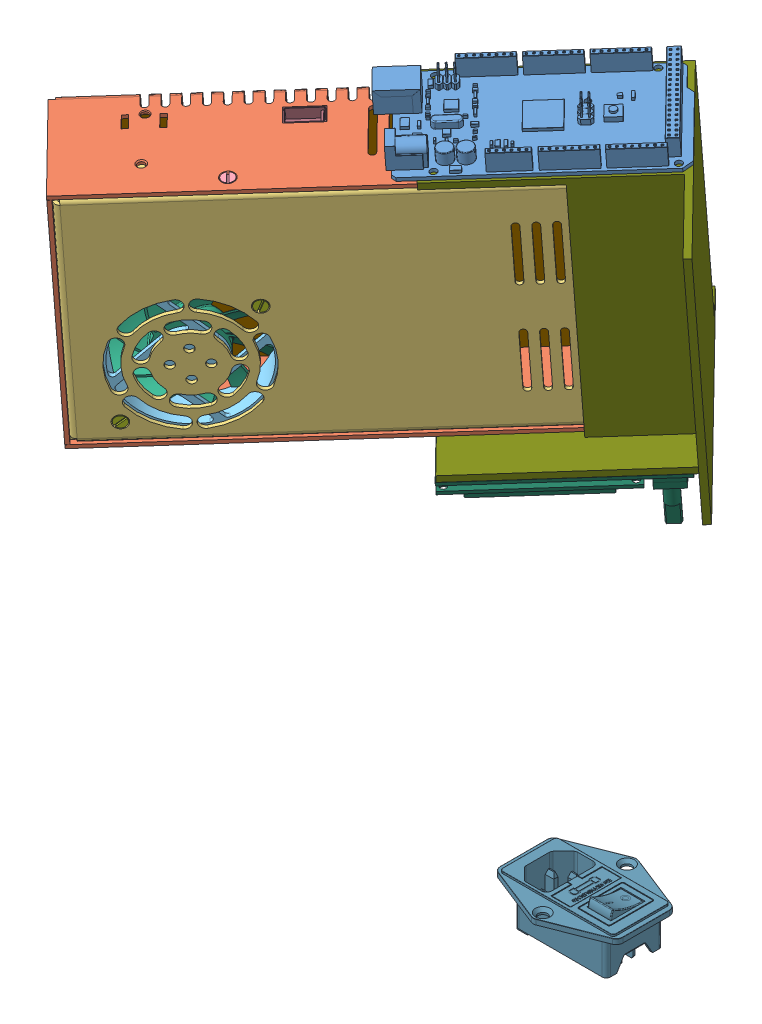
SolidWorks assembly _commandCenter, configuration Default. Lengths in mm.
Overall size (275.01 269.14 216.02).
51 component instances, 16 part files, 8 mates.
Components (placement in the parent):
- ArduinoMega-1: ArduinoMega [Default] at (-17.2246 278.8419 82.4218) x (-0.718489 -0.053184 0.693502) z (-0.041616 -0.991999 -0.119192) size (107.95 53.42 12.95)
- POWER 12V 30A.stp-1: POWER 12V 30A.stp [Default] at (-1.3313 279.7811 30.0341) x (0.718489 0.053184 -0.693502) z (-0.041616 -0.991999 -0.119192) size (215 51.26 117.39)
  - SWP (Basis).stp-1: SWP (Basis).stp [Default] at (0 1.75 57) x (1 0 0) z (0 1 0) size (215 114.01 51.26)
  - SWP (Deksel).stp-1: SWP (Deksel).stp [Default] at (-18.25 51.25 57) x (1 0 0) z (0 1 0) size (195 110.5 25.75)
  - Slotted Countersunk Flat Head Screw_DIN_ISO 2009 - M3 x 5 --- 5N.stp-1: Slotted Countersunk Flat Head Screw_DIN_ISO 2009 - M3 x 5 --- 5N.stp [Default] at (-154 44.75 114) x (0 0 -1) z (-0.992092 0.125515 0) size (5 5.5 5.44)
  - Slotted Countersunk Flat Head Screw_DIN_ISO 2009 - M3 x 5 --- 5N.stp-2: Slotted Countersunk Flat Head Screw_DIN_ISO 2009 - M3 x 5 --- 5N.stp [Default] at (-33 44.75 114) x (0 0 -1) z (0.278156 0.960536 0) size (5 5.5 5.44)
  - Slotted Countersunk Flat Head Screw_DIN_ISO 2009 - M3 x 5 --- 5N.stp-3: Slotted Countersunk Flat Head Screw_DIN_ISO 2009 - M3 x 5 --- 5N.stp [Default] at (-154 44.75 0) x (0 0 1) z (0 1 0) size (5 5.5 5.44)
  - Slotted Countersunk Flat Head Screw_DIN_ISO 2009 - M3 x 5 --- 5N.stp-4: Slotted Countersunk Flat Head Screw_DIN_ISO 2009 - M3 x 5 --- 5N.stp [Default] at (-33 44.75 0) x (0 0 1) z (-0.877705 -0.479201 0) size (5 5.5 5.44)
  - Slotted Countersunk Flat Head Screw_DIN_ISO 2009 - M3 x 5 --- 5N.stp-5: Slotted Countersunk Flat Head Screw_DIN_ISO 2009 - M3 x 5 --- 5N.stp [Default] at (-215 44.75 102) x (1 0 0) z (0 0.869235 -0.494399) size (5 5.5 5.44)
  - Slotted Countersunk Flat Head Screw_DIN_ISO 2009 - M3 x 5 --- 5N.stp-6: Slotted Countersunk Flat Head Screw_DIN_ISO 2009 - M3 x 5 --- 5N.stp [Default] at (-215 44.75 12) x (1 0 0) z (0 0.76206 0.647506) size (5 5.5 5.44)
  - Body 60mm fan.stp-1: Body 60mm fan.stp [Default] at (-170.75 34.3 77.75) x (1 0 0) z (0 1 0) size (59.5 59.5 15.2)
  - Propellor 60mm fan.stp-1: Propellor 60mm fan.stp [Default] at (-170.75 44.3 77.75) x (0.544808 0 -0.838561) z (0 1 0) size (57.61 57.23 10.4)
  - Slotted Countersunk Flat Head Screw_DIN_ISO 2009 - M3 x 20 --- 20N.stp-1: Slotted Countersunk Flat Head Screw_DIN_ISO 2009 - M3 x 20 --- 20N.stp [Default] at (-145.75 51.25 52.75) x (0 -1 0) z (0.364765 0 -0.9311) size (20 5.5 5.44)
  - Slotted Countersunk Flat Head Screw_DIN_ISO 2009 - M3 x 20 --- 20N.stp-2: Slotted Countersunk Flat Head Screw_DIN_ISO 2009 - M3 x 20 --- 20N.stp [Default] at (-195.75 51.25 102.75) x (0 -1 0) z (0.762204 0 -0.647337) size (20 5.5 5.44)
  - SWP (M3 moer).stp-1: SWP (M3 moer).stp [Default] at (-205 0 104.5) x (1 0 0) z (0 1 0) size (8.08 7 3.75)
  - SWP (M3 moer).stp-2: SWP (M3 moer).stp [Default] at (-205 0 9.5) x (1 0 0) z (0 1 0) size (8.08 7 3.75)
  - SWP (M3 moer).stp-3: SWP (M3 moer).stp [Default] at (-117.5 0 50.05) x (1 0 0) z (0 1 0) size (8.08 7 3.75)
  - SWP (M3 moer).stp-4: SWP (M3 moer).stp [Default] at (-27.5 0 104.5) x (1 0 0) z (0 1 0) size (8.08 7 3.75)
  - SWP (M3 moer).stp-5: SWP (M3 moer).stp [Default] at (-27.5 0 9.5) x (1 0 0) z (0 1 0) size (8.08 7 3.75)
  - SWP (PCB).stp-1: SWP (PCB).stp [Default] at (-1.75 9.75 57) x (1 0 0) z (0 1 0) size (211.5 110.5 15.9)
  - SWP (Montage draad).stp-1: SWP (Montage draad).stp [Default] at (-9.8 18.4 88.95) x (0 0 1) z (0 1 0) size (7 9.9 4.25)
  - SWP (Montage draad 2).stp-1: SWP (Montage draad 2).stp [Default] at (-9.8 18.4 88.95) x (1 0 0) z (0 1 0) size (7 7 1)
  - Slotted Cheese Head Screw_DIN_ISO 1207 - M4 x 5 --- 5N.stp-1: Slotted Cheese Head Screw_DIN_ISO 1207 - M4 x 5 --- 5N.stp [Default] at (-9.8 22 88.95) x (0 -1 0) z (0.939291 0 0.343123) size (7.6 7 7)
  - SWP (Montage draad).stp-2: SWP (Montage draad).stp [Default] at (-9.8 18.4 79.45) x (0 0 1) z (0 1 0) size (7 9.9 4.25)
  - SWP (Montage draad).stp-3: SWP (Montage draad).stp [Default] at (-9.8 18.4 69.95) x (0 0 1) z (0 1 0) size (7 9.9 4.25)
  - SWP (Montage draad).stp-4: SWP (Montage draad).stp [Default] at (-9.8 18.4 60.45) x (0 0 1) z (0 1 0) size (7 9.9 4.25)
  - SWP (Montage draad).stp-5: SWP (Montage draad).stp [Default] at (-9.8 18.4 50.95) x (0 0 1) z (0 1 0) size (7 9.9 4.25)
  - SWP (Montage draad).stp-6: SWP (Montage draad).stp [Default] at (-9.8 18.4 41.45) x (0 0 1) z (0 1 0) size (7 9.9 4.25)
  - SWP (Montage draad).stp-7: SWP (Montage draad).stp [Default] at (-9.8 18.4 31.95) x (0 0 1) z (0 1 0) size (7 9.9 4.25)
  - SWP (Montage draad).stp-8: SWP (Montage draad).stp [Default] at (-9.8 18.4 22.45) x (0 0 1) z (0 1 0) size (7 9.9 4.25)
  - SWP (Montage draad).stp-9: SWP (Montage draad).stp [Default] at (-9.8 18.4 12.95) x (0 0 1) z (0 1 0) size (7 9.9 4.25)
  - SWP (Montage draad 2).stp-2: SWP (Montage draad 2).stp [Default] at (-9.8 18.4 79.45) x (1 0 0) z (0 1 0) size (7 7 1)
  - SWP (Montage draad 2).stp-3: SWP (Montage draad 2).stp [Default] at (-9.8 18.4 69.95) x (1 0 0) z (0 1 0) size (7 7 1)
  - SWP (Montage draad 2).stp-4: SWP (Montage draad 2).stp [Default] at (-9.8 18.4 60.45) x (1 0 0) z (0 1 0) size (7 7 1)
  - SWP (Montage draad 2).stp-5: SWP (Montage draad 2).stp [Default] at (-9.8 18.4 50.95) x (1 0 0) z (0 1 0) size (7 7 1)
  - SWP (Montage draad 2).stp-6: SWP (Montage draad 2).stp [Default] at (-9.8 18.4 41.45) x (1 0 0) z (0 1 0) size (7 7 1)
  - SWP (Montage draad 2).stp-7: SWP (Montage draad 2).stp [Default] at (-9.8 18.4 31.95) x (1 0 0) z (0 1 0) size (7 7 1)
  - SWP (Montage draad 2).stp-8: SWP (Montage draad 2).stp [Default] at (-9.8 18.4 22.45) x (1 0 0) z (0 1 0) size (7 7 1)
  - SWP (Montage draad 2).stp-9: SWP (Montage draad 2).stp [Default] at (-9.8 18.4 12.95) x (1 0 0) z (0 1 0) size (7 7 1)
  - Slotted Cheese Head Screw_DIN_ISO 1207 - M4 x 5 --- 5N.stp-2: Slotted Cheese Head Screw_DIN_ISO 1207 - M4 x 5 --- 5N.stp [Default] at (-9.8 22 79.45) x (0 -1 0) z (0.939291 0 0.343123) size (7.6 7 7)
  - Slotted Cheese Head Screw_DIN_ISO 1207 - M4 x 5 --- 5N.stp-3: Slotted Cheese Head Screw_DIN_ISO 1207 - M4 x 5 --- 5N.stp [Default] at (-9.8 22 69.95) x (0 -1 0) z (0.939291 0 0.343123) size (7.6 7 7)
  - Slotted Cheese Head Screw_DIN_ISO 1207 - M4 x 5 --- 5N.stp-4: Slotted Cheese Head Screw_DIN_ISO 1207 - M4 x 5 --- 5N.stp [Default] at (-9.8 22 60.45) x (0 -1 0) z (0.939291 0 0.343123) size (7.6 7 7)
  - Slotted Cheese Head Screw_DIN_ISO 1207 - M4 x 5 --- 5N.stp-5: Slotted Cheese Head Screw_DIN_ISO 1207 - M4 x 5 --- 5N.stp [Default] at (-9.8 22 50.95) x (0 -1 0) z (0.939291 0 0.343123) size (7.6 7 7)
  - Slotted Cheese Head Screw_DIN_ISO 1207 - M4 x 5 --- 5N.stp-6: Slotted Cheese Head Screw_DIN_ISO 1207 - M4 x 5 --- 5N.stp [Default] at (-9.8 22 41.45) x (0 -1 0) z (0.939291 0 0.343123) size (7.6 7 7)
  - Slotted Cheese Head Screw_DIN_ISO 1207 - M4 x 5 --- 5N.stp-7: Slotted Cheese Head Screw_DIN_ISO 1207 - M4 x 5 --- 5N.stp [Default] at (-9.8 22 31.95) x (0 -1 0) z (0.939291 0 0.343123) size (7.6 7 7)
  - Slotted Cheese Head Screw_DIN_ISO 1207 - M4 x 5 --- 5N.stp-8: Slotted Cheese Head Screw_DIN_ISO 1207 - M4 x 5 --- 5N.stp [Default] at (-9.8 22 22.45) x (0 -1 0) z (0.939291 0 0.343123) size (7.6 7 7)
  - Slotted Cheese Head Screw_DIN_ISO 1207 - M4 x 5 --- 5N.stp-9: Slotted Cheese Head Screw_DIN_ISO 1207 - M4 x 5 --- 5N.stp [Default] at (-9.8 22 12.95) x (0 -1 0) z (0.939291 0 0.343123) size (7.6 7 7)
  - SWP (switch).stp-1: SWP (switch).stp [Default] at (-128.5 14.3 0) x (-1 0 0) z (0 0 -1) size (19 12.1 6)
- Fused AC Male Power Socket.stp-1: Fused AC Male Power Socket.stp [Default] at (85.1615 52.6208 165.0257) size (58.3 33.45 49.03)
- ReprapDiscountFullGraphicSmartController-Robotale_Dummy-1: ReprapDiscountFullGraphicSmartController-Robotale_Dummy [Défaut] at (-10.7298 153.7603 54.3951) x (0.694292 -0.114499 0.710527) z (-0.041616 -0.991999 -0.119192) size (93 87 37.5)
- glue-1: glue [Default] at (-1.1339 283.2602 26.1796) x (-0.041616 -0.991999 -0.119192) z (-0.694292 0.114499 -0.710527) size (120 93 116.88)
Mates (geometry in assembly coordinates):
- Parallel7: parallel aligned: plane of POWER 12V 30A.stp-1/SWP (Deksel).stp-1 through (18.7666 216.3985 72.3111) normal (0.718489 0.053184 -0.693502); plane of ReprapDiscountFullGraphicSmartController-Robotale_Dummy-1 through (40.8358 155.3853 69.0104) normal (0.718489 0.053184 -0.693502)
- Coincident3: coincident anti-aligned: plane of POWER 12V 30A.stp-1/SWP (Basis).stp-1 through (-2.4885 223.0368 24.4836) normal (0.718489 0.053184 -0.693502); plane of glue-1 through (-3.2894 283.1006 28.2601) normal (-0.718489 -0.053184 0.693502)
- Coincident4: coincident anti-aligned: plane of POWER 12V 30A.stp-1/SWP (Basis).stp-1 through (-4.8606 166.4929 17.6897) normal (-0.041616 -0.991999 -0.119192); plane of glue-1 through (-36.898 164.9094 42.0548) normal (0.041616 0.991999 0.119192)
- Coincident5: coincident anti-aligned: plane of POWER 12V 30A.stp-1/SWP (Basis).stp-1 through (-3.7035 223.2372 23.2402) normal (-0.694292 0.114499 -0.710527); plane of glue-1 through (-29.9461 280.6297 58.1318) normal (0.694292 -0.114499 0.710527)
- Coincident6: coincident anti-aligned: plane of ArduinoMega-1 through (-35.2493 271.4443 136.4317) normal (-0.041616 -0.991999 -0.119192); plane of glue-1 through (-3.2894 283.1006 28.2601) normal (0.041616 0.991999 0.119192)
- Parallel9: parallel aligned: plane of ArduinoMega-1 through (-69.9434 288.5075 110.9526) normal (-0.718489 -0.053184 0.693502); plane of glue-1 through (-67.9534 278.314 90.6753) normal (-0.718489 -0.053184 0.693502)
- Coincident8: coincident aligned: plane of ArduinoMega-1 through (0.6628 282.9639 28.0183) normal (0.718489 0.053184 -0.693502); plane of glue-1 through (-1.1339 283.2602 26.1796) normal (0.718489 0.053184 -0.693502)
- Coincident9: coincident anti-aligned: plane of ReprapDiscountFullGraphicSmartController-Robotale_Dummy-1 through (-10.5009 159.2163 55.0507) normal (0.041616 0.991999 0.119192); plane of glue-1 through (-8.2833 164.0608 13.9571) normal (-0.041616 -0.991999 -0.119192)
